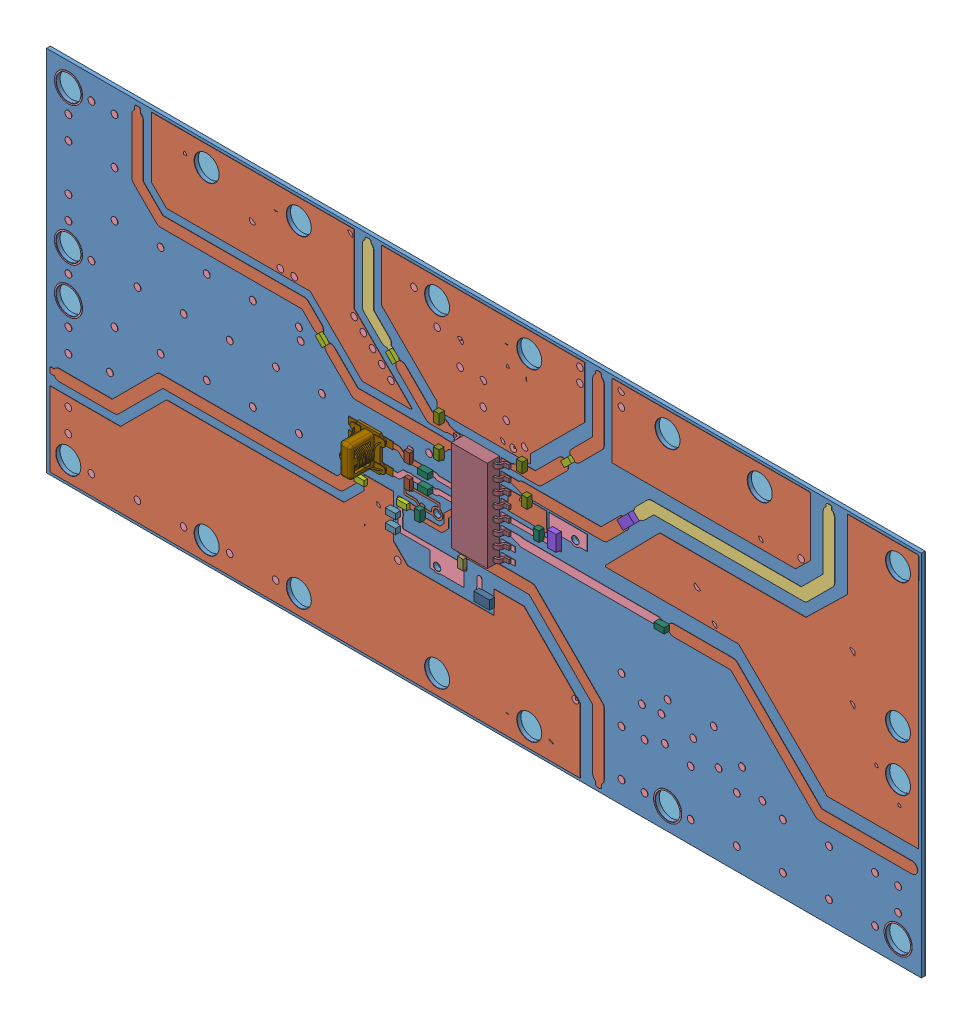
SolidWorks assembly PCB_AD8349, configuration По умолчанию. Lengths in mm.
Overall size (94.9 39.9 3.29).
32 component instances, 16 part files, 26 mates.
Components (placement in the parent):
- BoardOutline_PCB_AD8349-1: BoardOutline_PCB_AD8349 [По умолчанию] at origin size (94.9 39.9 0.41)
- Copper_Layer_Top LayerPCB_AD8349-1: Copper_Layer_Top LayerPCB_AD8349 [По умолчанию] at (0 0 0.4115) size (94.24 39.32 0.04)
  - Top Layer_PCB_AD8349_0-1: Top Layer_PCB_AD8349_0 [По умолчанию] at origin size (94.24 39.32 0.04)
  - Top Layer_PCB_AD8349_1-1: Top Layer_PCB_AD8349_1 [По умолчанию] at origin size (51.22 12.15 0.04)
  - Top Layer_PCB_AD8349_2-1: Top Layer_PCB_AD8349_2 [По умолчанию] at origin size (93.01 38.36 0.04)
- Copper_Layer_Bottom LayerPCB_AD8349-1: Copper_Layer_Bottom LayerPCB_AD8349 [По умолчанию] at (0 0 -0.0356) size (94.9 39.85 0.04)
  - Bottom Layer_PCB_AD8349_0-1: Bottom Layer_PCB_AD8349_0 [По умолчанию] at origin size (94.9 39.85 0.04)
  - Bottom Layer_PCB_AD8349_1-1: Bottom Layer_PCB_AD8349_1 [По умолчанию] at origin size (93.01 38.01 0.04)
- RESC1005L_i6124B5A08703F00000B_1-1: RESC1005L_i6124B5A08703F00000B_1 [По умолчанию] at (67.85 60.05 0.4115) x (0.707107 -0.707107 0) z (0 0 1) size (1.1 0.6 0.4)
- RESC1005L_i6124B5A08703F00000B_1-2: RESC1005L_i6124B5A08703F00000B_1 [По умолчанию] at (60.225 57.8 0.4115) x (0.707107 -0.707107 0) z (0 0 1) size (1.1 0.6 0.4)
- RESC1005L_i6124B5A08703F00000B_1-3: RESC1005L_i6124B5A08703F00000B_1 [По умолчанию] at (86.85 59.675 0.4115) x (0.707107 0.707107 0) z (0 0 1) size (1.1 0.6 0.4)
- RESC1005L_i6124B5A08703F00000B_1-4: RESC1005L_i6124B5A08703F00000B_1 [По умолчанию] at (69 46.75 0.4115) size (1.1 0.6 0.4)
- RESC1005L_i6124B5A08703F00000B_1-5: RESC1005L_i6124B5A08703F00000B_1 [По умолчанию] at (64.4 46.7 0.4115) size (1.1 0.6 0.4)
- RESC1608L_i6124B5A08711900002C_1-1: RESC1608L_i6124B5A08711900002C_1 [По умолчанию] at (93.5 57.5 0.4115) x (0.707107 0.707107 0) z (0 0 1) size (1.7 0.95 0.6)
- RESC1608L_i6124B5A08711900002C_1-2: RESC1608L_i6124B5A08711900002C_1 [По умолчанию] at (85.5 51.7 0.4115) x (0 1 0) z (0 0 1) size (1.7 0.95 0.6)
- TRANS_ETC1-1-13TR_ETC1-1-13TR_1-1: TRANS_ETC1-1-13TR_ETC1-1-13TR_1 [По умолчанию] at (65.3 50.2 0.4115) x (0 1 0) z (0 0 1) size (3.81 4.83 2.83)
- RESC1608L_i6124B5A08741A00000E_1-1: RESC1608L_i6124B5A08741A00000E_1 [По умолчанию] at (77.9 42.3 0.4115) size (1.7 0.95 0.6)
- RESC1005L_i6124B5A08703F00000A_1-1: RESC1005L_i6124B5A08703F00000A_1 [По умолчанию] at (69.6 51.5 0.4115) x (0 -1 0) z (0 0 1) size (1.1 0.6 0.4)
- RESC1005L_i6124B5A08703F00000A_1-2: RESC1005L_i6124B5A08703F00000A_1 [По умолчанию] at (69.6 49 0.4115) x (0 1 0) z (0 0 1) size (1.1 0.6 0.4)
- RESC1005L_i6124B5A08703F000005_1-1: RESC1005L_i6124B5A08703F000005_1 [По умолчанию] at (75.4 44.425 0.4115) x (0 -1 0) z (0 0 1) size (1.1 0.6 0.4)
- SOIC127P600X175-16N_AD8349_1-1: SOIC127P600X175-16N_AD8349_1 [По умолчанию] at (77.5 51.5 0.4115) size (6 9.9 1.53)
- CAPC1005L_i6124B5A087044000001_1-1: CAPC1005L_i6124B5A087044000001_1 [По умолчанию] at (68 45.5 0.4115) x (-1 0 0) z (0 0 1) size (1.1 0.6 0.6)
- CAPC1005L_i6124B5A087044000001_1-2: CAPC1005L_i6124B5A087044000001_1 [По умолчанию] at (68 44.1 0.4115) size (1.1 0.6 0.6)
- CAPC1005L_i6124B5A08727A000007_3-1: CAPC1005L_i6124B5A08727A000007_3 [По умолчанию] at (83.8 51.4 0.4115) x (0 1 0) z (0 0 1) size (1.1 0.6 0.6)
- CAPC1005L_i6124B5A08727A000007_3-2: CAPC1005L_i6124B5A08727A000007_3 [По умолчанию] at (97.147 49.3513 0.4115) size (1.1 0.6 0.6)
- CAPC1005L_i6124B5A08727A000007_3-3: CAPC1005L_i6124B5A08727A000007_3 [По умолчанию] at (71.5 49.5 0.4115) size (1.1 0.6 0.6)
- CAPC1005L_i6124B5A08727A000007_3-4: CAPC1005L_i6124B5A08727A000007_3 [По умолчанию] at (71.5 51 0.4115) size (1.1 0.6 0.6)
- CAPC1005L_i6124B5A08727A000007_3-5: CAPC1005L_i6124B5A08727A000007_3 [По умолчанию] at (70.9 46.8 0.4115) x (0 -1 0) z (0 0 1) size (1.1 0.6 0.6)
- CAPC1005L_i6124B5A087471000001_3-1: CAPC1005L_i6124B5A087471000001_3 [По умолчанию] at (82.525 53.875 0.4115) x (0 1 0) z (0 0 1) size (1.1 0.6 0.6)
- CAPC1005L_i6124B5A087471000001_3-2: CAPC1005L_i6124B5A087471000001_3 [По умолчанию] at (82 56.95 0.4115) x (0 1 0) z (0 0 1) size (1.1 0.6 0.6)
- CAPC1005L_i6124B5A087471000001_3-3: CAPC1005L_i6124B5A087471000001_3 [По умолчанию] at (73 57 0.4115) x (0 1 0) z (0 0 1) size (1.1 0.6 0.6)
- CAPC1005L_i6124B5A087471000001_3-4: CAPC1005L_i6124B5A087471000001_3 [По умолчанию] at (72.975 53.6 0.4115) x (0 1 0) z (0 0 1) size (1.1 0.6 0.6)
Mates (geometry in assembly coordinates):
- Совпадение2: coincident anti-aligned: plane of BoardOutline_PCB_AD8349-1 through (0 0 0.4115) normal (0 0 1); plane of Top Layer-1/Top Layer_PCB_AD8349_0-1 through (0 0 0.4115) normal (0 0 -1)
- Совпадение3: coincident anti-aligned: plane of BoardOutline_PCB_AD8349-1 through (0 0 0) normal (0 0 -1); plane of Bottom Layer-1/Bottom Layer_PCB_AD8349_0-1 through (0 0 0) normal (0 0 1)
- Расстояние1: distance = 0.4115 mm aligned: plane of R1-1 through (67.85 60.05 0.4115) normal (0 0 1); plane of BoardOutline_PCB_AD8349-1 through (0 0 0) normal (0 0 1)
- Расстояние2: distance = 0.4115 mm aligned: plane of R4-2 through (60.225 57.8 0.4115) normal (0 0 1); plane of BoardOutline_PCB_AD8349-1 through (0 0 0) normal (0 0 1)
- Расстояние3: distance = 0.4115 mm aligned: plane of R2-3 through (86.85 59.675 0.4115) normal (0 0 1); plane of BoardOutline_PCB_AD8349-1 through (0 0 0) normal (0 0 1)
- Расстояние4: distance = 0.4115 mm aligned: plane of R9-4 through (69 46.75 0.4115) normal (0 0 1); plane of BoardOutline_PCB_AD8349-1 through (0 0 0) normal (0 0 1)
- Расстояние5: distance = 0.4115 mm aligned: plane of R7-5 through (64.4 46.7 0.4115) normal (0 0 1); plane of BoardOutline_PCB_AD8349-1 through (0 0 0) normal (0 0 1)
- Расстояние6: distance = 0.4115 mm aligned: plane of R3-1 through (93.5 57.5 0.4115) normal (0 0 1); plane of BoardOutline_PCB_AD8349-1 through (0 0 0) normal (0 0 1)
- Расстояние7: distance = 0.4115 mm aligned: plane of R6-2 through (85.5 51.7 0.4115) normal (0 0 1); plane of BoardOutline_PCB_AD8349-1 through (0 0 0) normal (0 0 1)
- Расстояние8: distance = 0.4115 mm aligned: plane of T1-1 through (65.3 50.2 0.4115) normal (0 0 1); plane of BoardOutline_PCB_AD8349-1 through (0 0 0) normal (0 0 1)
- Расстояние9: distance = 0.4115 mm aligned: plane of R10-1 through (77.9 42.3 0.4115) normal (0 0 1); plane of BoardOutline_PCB_AD8349-1 through (0 0 0) normal (0 0 1)
- Расстояние10: distance = 0.4115 mm aligned: plane of R5-1 through (69.6 51.5 0.4115) normal (0 0 1); plane of BoardOutline_PCB_AD8349-1 through (0 0 0) normal (0 0 1)
- Расстояние11: distance = 0.4115 mm aligned: plane of R8-2 through (69.6 49 0.4115) normal (0 0 1); plane of BoardOutline_PCB_AD8349-1 through (0 0 0) normal (0 0 1)
- Расстояние12: distance = 0.4115 mm aligned: plane of R12-1 through (75.4 44.425 0.4115) normal (0 0 1); plane of BoardOutline_PCB_AD8349-1 through (0 0 0) normal (0 0 1)
- Расстояние13: distance = 0.4115 mm aligned: plane of D1-1 through (77.5 51.5 0.4115) normal (0 0 1); plane of BoardOutline_PCB_AD8349-1 through (0 0 0) normal (0 0 1)
- Расстояние14: distance = 0.4115 mm aligned: plane of C6-1 through (68 45.5 0.4115) normal (0 0 1); plane of BoardOutline_PCB_AD8349-1 through (0 0 0) normal (0 0 1)
- Расстояние15: distance = 0.4115 mm aligned: plane of C10-2 through (68 44.1 0.4115) normal (0 0 1); plane of BoardOutline_PCB_AD8349-1 through (0 0 0) normal (0 0 1)
- Расстояние16: distance = 0.4115 mm aligned: plane of C5-1 through (83.8 51.4 0.4115) normal (0 0 1); plane of BoardOutline_PCB_AD8349-1 through (0 0 0) normal (0 0 1)
- Расстояние17: distance = 0.4115 mm aligned: plane of C9-2 through (97.147 49.3513 0.4115) normal (0 0 1); plane of BoardOutline_PCB_AD8349-1 through (0 0 0) normal (0 0 1)
- Расстояние18: distance = 0.4115 mm aligned: plane of C8-3 through (71.5 49.5 0.4115) normal (0 0 1); plane of BoardOutline_PCB_AD8349-1 through (0 0 0) normal (0 0 1)
- Расстояние19: distance = 0.4115 mm aligned: plane of C7-4 through (71.5 51 0.4115) normal (0 0 1); plane of BoardOutline_PCB_AD8349-1 through (0 0 0) normal (0 0 1)
- Расстояние20: distance = 0.4115 mm aligned: plane of C11-5 through (70.9 46.8 0.4115) normal (0 0 1); plane of BoardOutline_PCB_AD8349-1 through (0 0 0) normal (0 0 1)
- Расстояние21: distance = 0.4115 mm aligned: plane of C4-1 through (82.525 53.875 0.4115) normal (0 0 1); plane of BoardOutline_PCB_AD8349-1 through (0 0 0) normal (0 0 1)
- Расстояние22: distance = 0.4115 mm aligned: plane of C2-2 through (82 56.95 0.4115) normal (0 0 1); plane of BoardOutline_PCB_AD8349-1 through (0 0 0) normal (0 0 1)
- Расстояние23: distance = 0.4115 mm aligned: plane of C1-3 through (73 57 0.4115) normal (0 0 1); plane of BoardOutline_PCB_AD8349-1 through (0 0 0) normal (0 0 1)
- Расстояние24: distance = 0.4115 mm aligned: plane of C3-4 through (72.975 53.6 0.4115) normal (0 0 1); plane of BoardOutline_PCB_AD8349-1 through (0 0 0) normal (0 0 1)
